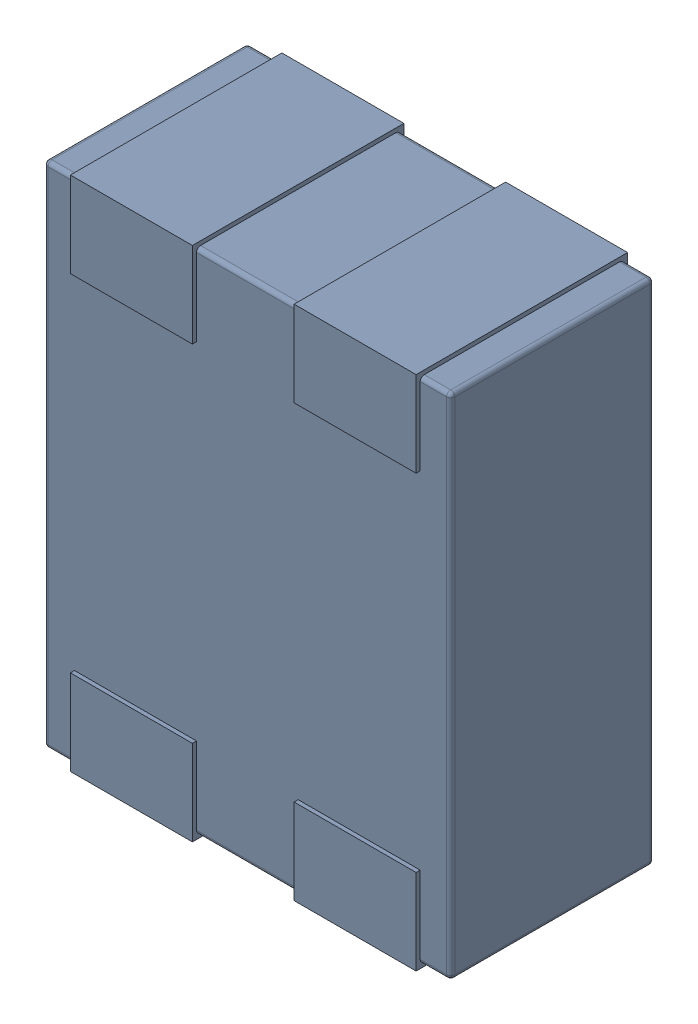
SolidWorks assembly L19, configuration Défaut. Lengths in mm.
Overall size (1 1.27 0.52).
4 component instances, 1 part files, 0 mates.
Components (placement in the parent):
- MCZ1210DH900L2TA0G-1: MCZ1210DH900L2TA0G [Défaut] at (53.3862 -40.4272 -1.6) x (-1 0 0) z (0 0 1) size (1 1.27 0.52)
  - 3D_PCB1_2021-12-30 (1).step-1: 3D_PCB1_2021-12-30 (1).step [Défaut] at origin size (1 1.27 0.52)
    - a3ec64f90eb5404ebd79eca0046a794a.step-1: a3ec64f90eb5404ebd79eca0046a794a.step [Défaut] at (5.0419 -6.8961 1.6) size (1 1.27 0.52)
      - SOLID.step_650-1: SOLID.step_650 [Défaut] at origin size (1 1.27 0.52)
